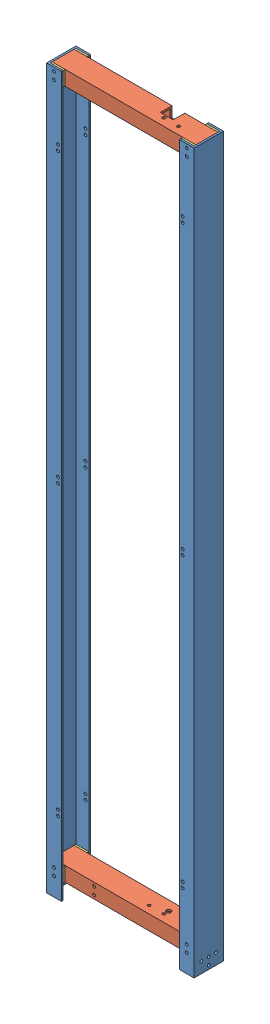
SolidWorks assembly Stage2UASYY, configuration Default. Lengths in mm.
Overall size (255.27 1244.6 50.8).
12 component instances, 3 part files, 33 mates.
Components (placement in the parent):
- SECONDSTAGELONG-1: SECONDSTAGELONG [Default] at (239.3967 -71.8294 1160.1387) size (25.4 1244.6 50.8)
- SECONDSTAGELONG-2: SECONDSTAGELONG [Default] at (494.6667 -71.8294 1109.3387) x (-1 0 0) z (0 0 -1) size (25.4 1244.6 50.8)
- SECONDSTAGECROSS-1: SECONDSTAGECROSS [Top] at (491.4917 1147.3706 1153.7887) x (0 1 0) z (0 0 1) size (25.4 248.92 38.1)
- SECONDSTAGECROSS-2: SECONDSTAGECROSS [Bottom] at (491.4917 -46.4294 1153.7887) x (0 1 0) z (0 0 1) size (25.4 248.92 38.1)
- 20-idk Spacers for second stage-1: 20-idk Spacers for second stage [Rev 1.1] at (491.4917 -46.4294 1153.7887) x (0 1 0) z (0 0 1) size (25.4 22.22 3.12)
- 20-idk Spacers for second stage-2: 20-idk Spacers for second stage [Rev 1.1] at (491.4917 -46.4294 1112.5137) x (0 1 0) z (0 0 1) size (25.4 22.22 3.12)
- 20-idk Spacers for second stage-3: 20-idk Spacers for second stage [Rev 1.1] at (491.4917 1147.3706 1153.7379) x (0 1 0) z (0 0 1) size (25.4 22.22 3.12)
- 20-idk Spacers for second stage-4: 20-idk Spacers for second stage [Rev 1.1] at (491.4917 1147.3706 1112.5137) x (0 1 0) z (0 0 1) size (25.4 22.22 3.12)
- 20-idk Spacers for second stage-5: 20-idk Spacers for second stage [Rev 1.1] at (242.5717 1172.7706 1112.5137) x (0 -1 0) z (0 0 1) size (25.4 22.22 3.12)
- 20-idk Spacers for second stage-6: 20-idk Spacers for second stage [Rev 1.1] at (242.5717 1172.7706 1153.7379) x (0 -1 0) z (0 0 1) size (25.4 22.22 3.12)
- 20-idk Spacers for second stage-7: 20-idk Spacers for second stage [Rev 1.1] at (242.5717 -21.0294 1112.5137) x (0 -1 0) z (0 0 1) size (25.4 22.22 3.12)
- 20-idk Spacers for second stage-8: 20-idk Spacers for second stage [Rev 1.1] at (242.5717 -46.4294 1156.9637) x (0 1 0) z (0 0 -1) size (25.4 22.22 3.12)
Mates (geometry in assembly coordinates):
- Coincident1: coincident anti-aligned: plane of SECONDSTAGELONG-1 through (242.5717 1172.7706 1160.1387) normal (1 0 0); plane of SECONDSTAGECROSS-1 through (242.5717 1147.3706 1153.7887) normal (-1 0 0)
- Coincident2: coincident anti-aligned: line of SECONDSTAGELONG-1 through (242.5717 1172.7706 1112.5137) axis (0 0 1); line of SECONDSTAGECROSS-1 through (242.5717 1172.7706 1153.7887) axis (0 0 -1)
- Width1: width aligned: plane of SECONDSTAGELONG-1 through (239.3967 1172.7706 1112.5137) normal (0 0 1); plane of SECONDSTAGELONG-1 through (239.3967 1172.7706 1156.9637) normal (0 0 -1); plane of SECONDSTAGECROSS-1 through (242.5717 1147.3706 1153.7887) normal (0 0 1); plane of SECONDSTAGECROSS-1 through (242.5717 1147.3706 1115.6887) normal (0 0 -1)
- Coincident7: coincident anti-aligned: plane of SECONDSTAGELONG-2 through (491.4917 1172.7706 1109.3387) normal (-1 0 0); plane of SECONDSTAGECROSS-1 through (491.4917 1147.3706 1153.7887) normal (1 0 0)
- Coincident8: coincident aligned: line of SECONDSTAGELONG-2 through (491.4917 1172.7706 1156.9637) axis (0 0 -1); line of SECONDSTAGECROSS-1 through (491.4917 1172.7706 1153.7887) axis (0 0 -1)
- Width2: width anti-aligned: plane of SECONDSTAGELONG-2 through (494.6667 1172.7706 1156.9637) normal (0 0 -1); plane of SECONDSTAGELONG-2 through (494.6667 1172.7706 1112.5137) normal (0 0 1); plane of SECONDSTAGECROSS-1 through (242.5717 1147.3706 1153.7887) normal (0 0 1); plane of SECONDSTAGECROSS-1 through (242.5717 1147.3706 1115.6887) normal (0 0 -1)
- Coincident9: coincident anti-aligned: plane of SECONDSTAGELONG-1 through (242.5717 1172.7706 1160.1387) normal (1 0 0); plane of SECONDSTAGECROSS-2 through (242.5717 -46.4294 1153.7887) normal (-1 0 0)
- Width3: width anti-aligned: plane of SECONDSTAGELONG-1 through (239.3967 1172.7706 1156.9637) normal (0 0 -1); plane of SECONDSTAGELONG-1 through (239.3967 1172.7706 1112.5137) normal (0 0 1); plane of SECONDSTAGECROSS-2 through (242.5717 -46.4294 1153.7887) normal (0 0 1); plane of SECONDSTAGECROSS-2 through (242.5717 -46.4294 1115.6887) normal (0 0 -1)
- Distance1: distance = 25.4 mm: line of SECONDSTAGECROSS-2 through (242.5717 -46.4294 1115.6887) axis (0 0 1); line of SECONDSTAGELONG-1 through (242.5717 -71.8294 1112.5137) axis (0 0 1)
- InPlace1: in place: plane of ? through (242.5717 -46.4294 1153.7887) normal (0 0 1); plane of ? through (0 0 1153.7887) normal (0 0 1); moOrthogonalPlaneRef_w of ? through (242.5717 -46.4294 1153.7887) normal (0 0 1); plane of ? through (0 0 1153.7887) normal (0 1 0); plane of ? through (242.5717 -46.4294 1153.7887) normal (0 0 1); plane of ? through (0 0 1153.7887) normal (1 0 0); plane of ? through (242.5717 -46.4294 1153.7887) normal (0 0 1); unknown of ?
- Coincident10: coincident aligned: plane of SECONDSTAGECROSS-2; plane of 20-idk Spacers for second stage-1
- Coincident11: coincident aligned: moOrthogonalPlaneRef_w of SECONDSTAGECROSS-2 through (491.4917 -46.4294 1153.7887) normal (-1 0 0); plane of 20-idk Spacers for second stage-1 through (491.4917 -46.4294 1153.7887) normal (-1 0 0)
- Coincident12: coincident anti-aligned: moOrthogonalPlaneRef_w of SECONDSTAGECROSS-2 through (491.4917 -46.4294 1153.7887) normal (0 -1 0); plane of 20-idk Spacers for second stage-1 through (491.4917 -46.4294 1153.7887) normal (0 1 0)
- Coincident14: coincident anti-aligned: plane of SECONDSTAGECROSS-2 through (242.5717 -46.4294 1115.6887) normal (0 0 -1); plane of 20-idk Spacers for second stage-7 through (242.5717 -21.0294 1115.6887) normal (0 0 1)
- Coincident15: coincident anti-aligned: plane of SECONDSTAGECROSS-2 through (242.5717 -46.4294 1115.6887) normal (0 0 -1); plane of 20-idk Spacers for second stage-2 through (491.4917 -46.4294 1115.6887) normal (0 0 1)
- Coincident16: coincident anti-aligned: plane of SECONDSTAGECROSS-1 through (242.5717 1147.3706 1115.6887) normal (0 0 -1); plane of 20-idk Spacers for second stage-5 through (242.5717 1172.7706 1115.6887) normal (0 0 1)
- Coincident18: coincident anti-aligned: plane of SECONDSTAGECROSS-1 through (242.5717 1147.3706 1115.6887) normal (0 0 -1); plane of 20-idk Spacers for second stage-4 through (491.4917 1147.3706 1115.6887) normal (0 0 1)
- Coincident20: coincident aligned: plane of SECONDSTAGECROSS-1 through (242.5717 1172.7706 1153.7887) normal (0 1 0); plane of 20-idk Spacers for second stage-3 through (491.4917 1172.7706 1156.9129) normal (0 1 0)
- Coincident21: coincident aligned: plane of SECONDSTAGECROSS-1 through (242.5717 1172.7706 1153.7887) normal (0 1 0); plane of 20-idk Spacers for second stage-4 through (491.4917 1172.7706 1115.6887) normal (0 1 0)
- Coincident22: coincident: plane of SECONDSTAGELONG-1 through (242.5717 1172.7706 1160.1387) normal (1 0 0); line of 20-idk Spacers for second stage-4 through (242.5717 1172.7706 1115.6887) axis (0 0 -1)
- Coincident23: coincident: plane of SECONDSTAGELONG-1 through (242.5717 1172.7706 1160.1387) normal (1 0 0); line of 20-idk Spacers for second stage-3 through (242.5717 1172.7706 1156.9129) axis (0 0 -1)
- Coincident28: coincident aligned: plane of SECONDSTAGECROSS-2 through (242.5717 -46.4294 1153.7887) normal (0 -1 0); plane of 20-idk Spacers for second stage-8 through (242.5717 -46.4294 1153.7887) normal (0 -1 0)
- Coincident31: coincident anti-aligned: plane of SECONDSTAGELONG-2 through (491.4917 1172.7706 1109.3387) normal (-1 0 0); plane of 20-idk Spacers for second stage-8 through (491.4917 -46.4294 1153.7887) normal (1 0 0)
- Coincident32: coincident anti-aligned: plane of SECONDSTAGECROSS-2 through (242.5717 -46.4294 1153.7887) normal (0 0 1); plane of 20-idk Spacers for second stage-8 through (242.5717 -46.4294 1153.7887) normal (0 0 -1)
- Coincident33: coincident aligned: plane of SECONDSTAGECROSS-2 through (242.5717 -46.4294 1153.7887) normal (0 -1 0); plane of 20-idk Spacers for second stage-7 through (242.5717 -46.4294 1115.6887) normal (0 -1 0)
- Coincident35: coincident aligned: plane of SECONDSTAGECROSS-1 through (242.5717 1172.7706 1153.7887) normal (0 1 0); plane of 20-idk Spacers for second stage-6 through (242.5717 1172.7706 1156.9129) normal (0 1 0)
- Coincident36: coincident anti-aligned: plane of SECONDSTAGELONG-2 through (491.4917 1172.7706 1109.3387) normal (-1 0 0); plane of 20-idk Spacers for second stage-6 through (491.4917 1172.7706 1156.9129) normal (1 0 0)
- Coincident37: coincident anti-aligned: plane of SECONDSTAGELONG-2 through (491.4917 1172.7706 1109.3387) normal (-1 0 0); plane of 20-idk Spacers for second stage-5 through (491.4917 1172.7706 1115.6887) normal (1 0 0)
- Coincident38: coincident aligned: plane of SECONDSTAGECROSS-1 through (242.5717 1172.7706 1153.7887) normal (0 1 0); plane of 20-idk Spacers for second stage-5 through (242.5717 1172.7706 1115.6887) normal (0 1 0)
- Coincident39: coincident anti-aligned: plane of SECONDSTAGELONG-1 through (242.5717 1172.7706 1160.1387) normal (1 0 0); plane of 20-idk Spacers for second stage-2 through (242.5717 -46.4294 1115.6887) normal (-1 0 0)
- Coincident40: coincident aligned: plane of SECONDSTAGECROSS-2 through (242.5717 -21.0294 1153.7887) normal (0 1 0); plane of 20-idk Spacers for second stage-2 through (491.4917 -21.0294 1115.6887) normal (0 1 0)
- Coincident41: coincident aligned: plane of 20-idk Spacers for second stage-3 through (491.4917 1147.3706 1156.9129) normal (0 0 1); plane of 20-idk Spacers for second stage-6 through (242.5717 1172.7706 1156.9129) normal (0 0 1)
- Coincident42: coincident aligned: plane of 20-idk Spacers for second stage-3 through (491.4917 1147.3706 1156.9129) normal (0 0 1); plane of 20-idk Spacers for second stage-8 through (469.2667 -21.0294 1156.9129) normal (0 0 1)
